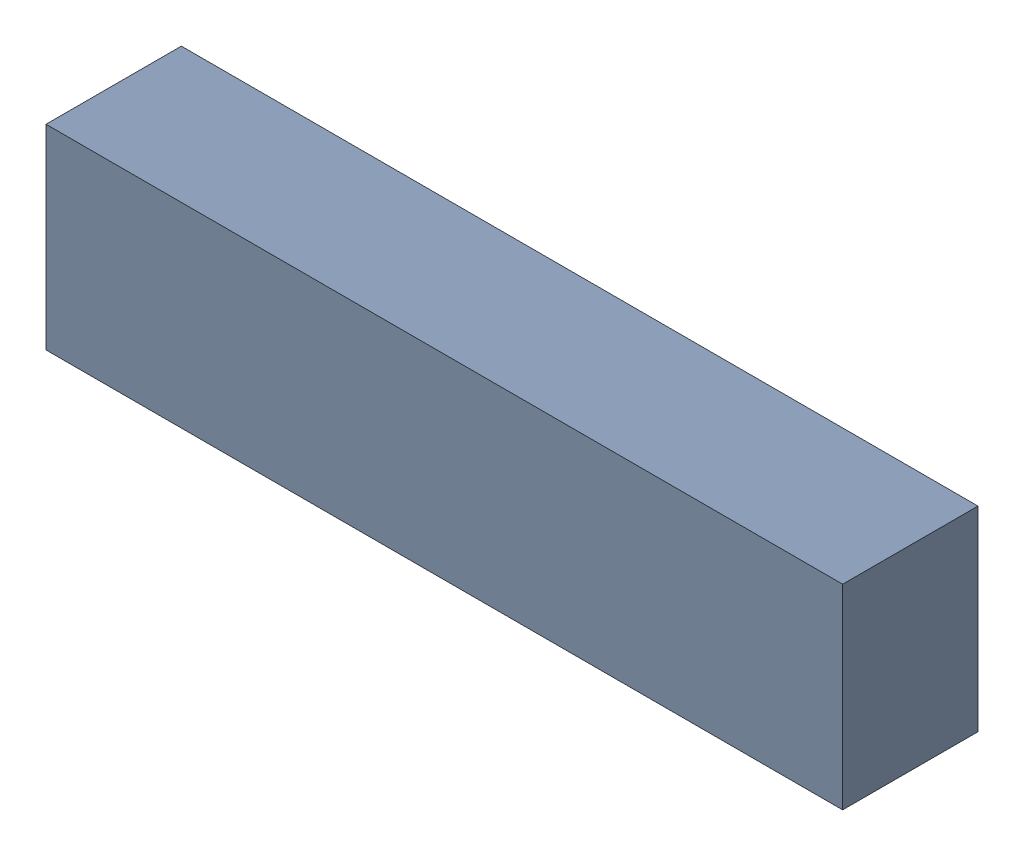
SolidWorks assembly Imported, configuration Default. Lengths in mm.
Overall size (26.9 6.6 4.57).
2 component instances, 1 part files, 0 mates.
Components (placement in the parent):
- -1733503016-1: -1733503016 [Default] at (473.897 283.063 0.51) size (26.9 6.6 4.57)
  - Extruded_5-1: Extruded_5 [Default] at origin size (26.9 6.6 4.57)
